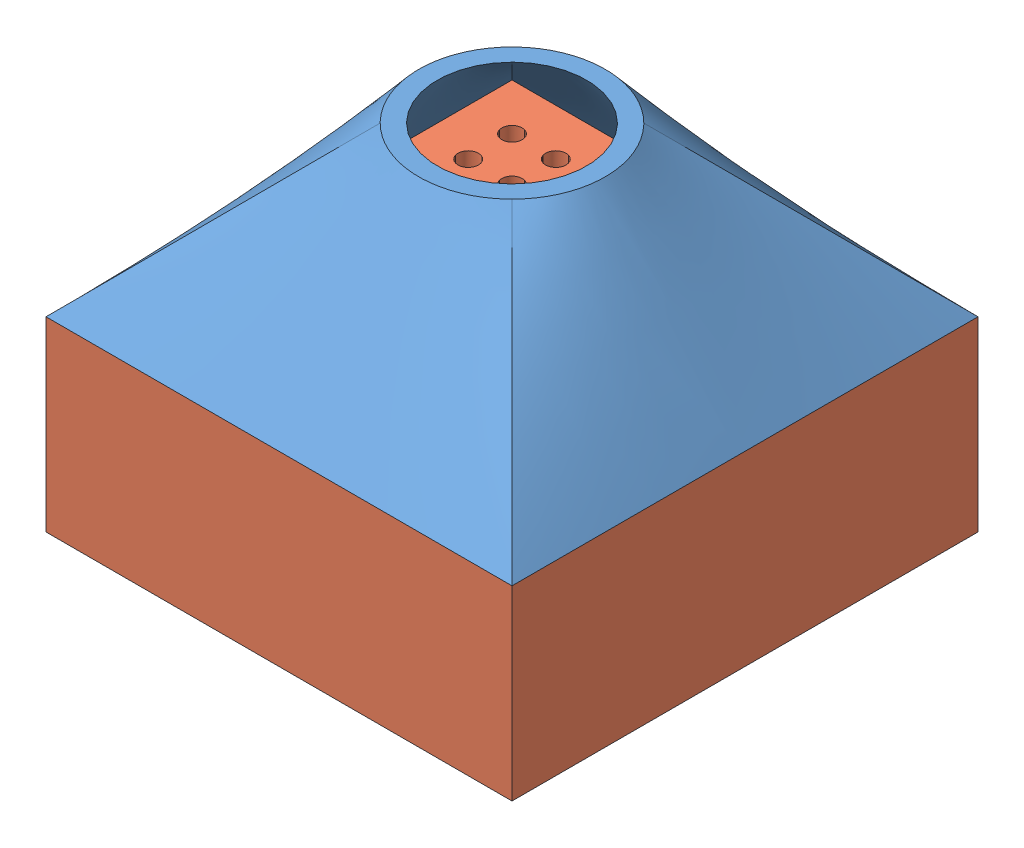
SolidWorks assembly Assem1, configuration Default. Lengths in mm.
Overall size (25.01 19.01 25.01).
2 component instances, 2 part files, 3 mates.
Components (placement in the parent):
- OpenFiberCouple-1: OpenFiberCouple [Default] at (9.7826 24.5967 14.1803) size (25.01 9.02 25.01)
- PMTMatrix-1: PMTMatrix [Default] at (9.7826 5.5967 14.1803) size (25 10 25)
Mates (geometry in assembly coordinates):
- Coincident1: coincident: plane of OpenFiberCouple-1 through (9.7826 15.5967 14.1803) normal (0 -1 0); plane of PMTMatrix-1 through (23.9951 15.5967 14.1803) normal (0 1 0)
- Coincident3: coincident: line of OpenFiberCouple-1 through (-2.7174 15.5967 1.6803) axis (1 0 0); line of PMTMatrix-1 through (22.2826 15.5967 1.6803) axis (-1 0 0)
- Coincident4: coincident aligned: line of OpenFiberCouple-1 through (-2.7174 15.5967 1.6803) axis (0 0 1); line of PMTMatrix-1 through (-2.7174 15.5967 1.6803) axis (0 0 1)
